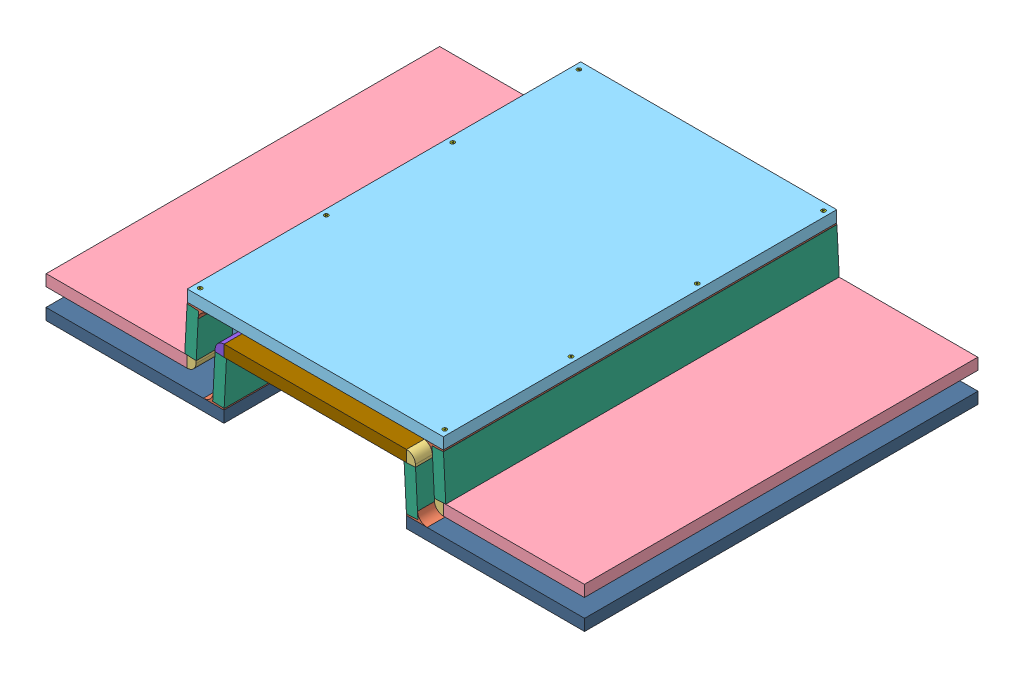
SolidWorks assembly Assemblage moule, configuration Default. Lengths in mm.
Overall size (752.9 137 550).
38 component instances, 11 part files, 25 mates.
Components (placement in the parent):
- Plancher simple-1: Plancher simple [Default] at (125.6276 24.22 73.6954) size (658.2 105 450)
- Female mold-1: Female mold [Default] at (-266.2243 -94.1216 86.2035) size (752.28 96 550)
  - A1-1: A1 [Default] at (542.1283 143.3416 262.4919) x (1 0 0) z (0 0 -1) size (28.69 12.79 550)
  - A1-2: A1 [Default] at (241.5754 143.3416 -287.5081) x (-1 0 0) z (0 0 1) size (28.69 12.79 550)
  - A2-1: A2 [Default] at (212.711 75.8416 262.4919) x (-1 0 0) z (0 0 -1) size (12.66 15.98 550)
  - A2-2: A2 [Default] at (570.9927 75.8416 -287.5081) size (12.66 15.98 550)
  - P1-1: P1 [Default] at (114.211 63.3416 -12.5081) x (1 0 0) z (0 1 0) size (197 550 16)
  - P1-2: P1 [Default] at (669.4927 63.3416 -12.5081) x (1 0 0) z (0 1 0) size (197 550 16)
  - P2-1: P2 [Default] at (391.8504 143.3416 -12.5081) x (1 0 0) z (0 1 0) size (357.94 550 16)
  - P3-1: P3 [Default] at (556.7069 109.5893 -12.5081) x (0 0 -1) z (0.99863 0.052336 0) size (550 61.94 16)
  - P3-2: P3 [Default] at (226.9968 109.5893 -12.5081) x (0 0 -1) z (-0.99863 0.052336 0) size (550 61.94 16)
  - 90031A117_Phillips Flat Head Screws for Wood-1: 90031A117_Phillips Flat Head Screws for Wood [90031A117] at (220.8804 143.4666 252.4919) x (0 -1 0) z (0.999698 0 -0.024591) size (31.75 5.71 5.71)
  - 90031A117_Phillips Flat Head Screws for Wood-2: 90031A117_Phillips Flat Head Screws for Wood [90031A117] at (220.8804 143.4666 75.9919) x (0 -1 0) z (0.999698 0 -0.024591) size (31.75 5.71 5.71)
  - 90031A117_Phillips Flat Head Screws for Wood-3: 90031A117_Phillips Flat Head Screws for Wood [90031A117] at (220.8804 143.4666 -100.5081) x (0 -1 0) z (0.981484 0 -0.191546) size (31.75 5.71 5.71)
  - 90031A117_Phillips Flat Head Screws for Wood-4: 90031A117_Phillips Flat Head Screws for Wood [90031A117] at (220.8804 143.4666 -277.0081) x (0 -1 0) z (-0.266658 0 -0.963791) size (31.75 5.71 5.71)
  - 90031A117_Phillips Flat Head Screws for Wood-5: 90031A117_Phillips Flat Head Screws for Wood [90031A117] at (562.8204 143.4666 252.4919) x (0 -1 0) z (0.981484 0 -0.191546) size (31.75 5.71 5.71)
  - 90031A117_Phillips Flat Head Screws for Wood-6: 90031A117_Phillips Flat Head Screws for Wood [90031A117] at (562.8204 143.4666 75.9919) x (0 -1 0) z (0.981484 0 -0.191546) size (31.75 5.71 5.71)
  - 90031A117_Phillips Flat Head Screws for Wood-7: 90031A117_Phillips Flat Head Screws for Wood [90031A117] at (562.8204 143.4666 -100.5081) x (0 -1 0) z (0.981484 0 -0.191546) size (31.75 5.71 5.71)
  - 90031A117_Phillips Flat Head Screws for Wood-8: 90031A117_Phillips Flat Head Screws for Wood [90031A117] at (562.8204 143.4666 -277.0081) x (0 -1 0) z (0.981484 0 -0.191546) size (31.75 5.71 5.71)
- anneau_rover-2: anneau_rover [Default] at (126.4473 -2.45 41.3303) size (255.02 26.67 255.02) (hidden)
- Male mold-1: Male mold [Default] at (-12.1046 77.452 -208.4078) size (752.9 96 550)
  - A4-1: A4 [Default] at (10.2322 -65.7319 557.1032) x (1 0 0) z (0 0 -1) size (12.66 15.98 550)
  - A1-1: A1 [Default] at (294.0966 -133.2319 557.1032) x (-1 0 0) z (0 0 -1) size (28.69 12.79 550)
  - A2-1: A2 [Default] at (265.2322 -65.7319 7.1032) x (-1 0 0) z (0 0 1) size (12.66 15.98 550)
  - A1-2: A1 [Default] at (-18.6322 -133.2319 7.1032) size (28.69 12.79 550)
  - P5-1: P5 [Default] at (137.7322 -69.2319 282.1032) x (1 0 0) z (0 1 0) size (255 550 16)
  - P3-1: P3 [Default] at (263.5399 -100.317 282.1032) x (0 0 -1) z (0.99863 0.052336 0) size (550 61.94 16)
  - P3-2: P3 [Default] at (-4.0536 -99.4805 282.1032) x (0 0 -1) z (0.99863 -0.052336 0) size (550 61.94 16)
  - P6-1: P6 [Default] at (389.7916 -133.2319 282.1032) x (-1 0 0) z (0 -1 0) size (248.78 550 16)
  - P6-2: P6 [Default] at (-114.3272 -133.2319 282.1032) x (1 0 0) z (0 -1 0) size (248.78 550 16)
  - 90031A117_Phillips Flat Head Screws for Wood-1: 90031A117_Phillips Flat Head Screws for Wood [90031A117] at (2.0628 -133.3569 17.6032) x (0 1 0) z (0.999698 0 0.024591) size (31.75 5.71 5.71)
  - 90031A117_Phillips Flat Head Screws for Wood-16: 90031A117_Phillips Flat Head Screws for Wood [90031A117] at (2.0628 -133.3569 194.1032) x (0 1 0) z (0.986419 0 -0.164247) size (31.75 5.71 5.71)
  - 90031A117_Phillips Flat Head Screws for Wood-17: 90031A117_Phillips Flat Head Screws for Wood [90031A117] at (2.0628 -133.3569 370.6032) x (0 1 0) z (0.927819 0 -0.373031) size (31.75 5.71 5.71)
  - 90031A117_Phillips Flat Head Screws for Wood-18: 90031A117_Phillips Flat Head Screws for Wood [90031A117] at (2.0628 -133.3569 547.1032) x (0 1 0) z (0.814513 0 -0.580145) size (31.75 5.71 5.71)
  - 90031A117_Phillips Flat Head Screws for Wood-19: 90031A117_Phillips Flat Head Screws for Wood [90031A117] at (273.4016 -133.3569 17.1032) x (0 1 0) z (0.652414 0 -0.757863) size (31.75 5.71 5.71)
  - 90031A117_Phillips Flat Head Screws for Wood-21: 90031A117_Phillips Flat Head Screws for Wood [90031A117] at (273.4016 -133.3569 193.6032) x (0 1 0) z (0.465534 0 -0.88503) size (31.75 5.71 5.71)
  - 90031A117_Phillips Flat Head Screws for Wood-27: 90031A117_Phillips Flat Head Screws for Wood [90031A117] at (273.4016 -133.3569 370.1032) x (0 1 0) z (0.290404 0 -0.956904) size (31.75 5.71 5.71)
  - 90031A117_Phillips Flat Head Screws for Wood-29: 90031A117_Phillips Flat Head Screws for Wood [90031A117] at (273.4016 -133.3569 546.6032) x (0 1 0) z (0.077293 0 -0.997008) size (31.75 5.71 5.71)
Mates (geometry in assembly coordinates):
- Coincident118: coincident anti-aligned: plane of Plancher simple-1 through (-203.4724 -30.78 -151.3046) normal (0 1 0); plane of Female mold-1/P1-1 through (-152.0133 -30.78 73.6954) normal (0 -1 0)
- Coincident119: coincident: point of Plancher simple-1; unknown of Female mold-1/P1-1
- Coincident121: coincident anti-aligned: plane of Plancher simple-1 through (454.7276 -30.78 -151.3046) normal (0 1 0); plane of Female mold-1/P1-2 through (403.2684 -30.78 73.6954) normal (0 -1 0)
- Coincident122: coincident: unknown of Plancher simple-1; unknown of Female mold-1/P1-2
- Coincident124: coincident anti-aligned: plane of Plancher simple-1 through (-24.6476 49.22 -151.3046) normal (0 1 0); plane of Female mold-1/P2-1 through (125.6261 49.22 73.6954) normal (0 -1 0)
- Parallel10: parallel aligned: plane of Plancher simple-1 through (-53.5133 -18.28 -151.3046) normal (0 0 -1); plane of Female mold-1/P2-1 through (-53.3439 65.22 -201.3046) normal (0 0 -1)
- Coincident125: coincident anti-aligned: plane of Plancher simple-1 through (292.2856 -18.9342 -151.3046) normal (0.99863 0.052336 0); plane of Female mold-1/P3-1 through (290.4826 15.4677 73.6954) normal (-0.99863 -0.052336 0)
- Concentric27: concentric aligned: cylinder of Plancher simple-1 through (275.9027 35.72 -151.3046) axis (0 0 1) radius 13.5; cylinder of Female mold-1/A1-1 through (275.9027 35.72 -201.3046) axis (0 0 1) radius 13.5
- Concentric28: concentric anti-aligned: cylinder of Plancher simple-1 through (-24.6476 35.72 -151.3046) axis (0 0 1) radius 13.5; cylinder of Female mold-1/A1-2 through (-24.6476 35.72 348.6954) axis (0 0 -1) radius 13.5
- Coincident126: coincident anti-aligned: plane of Plancher simple-1 through (-41.0304 -18.9342 -151.3046) normal (-0.99863 0.052336 0); plane of Female mold-1/P3-2 through (-39.2275 15.4677 73.6954) normal (0.99863 -0.052336 0)
- Concentric29: concentric aligned: cylinder of Plancher simple-1 through (-53.5133 -18.28 -151.3046) axis (0 0 1) radius 12.5; cylinder of Female mold-1/A2-1 through (-53.5133 -18.28 -201.3046) axis (0 0 1) radius 12.5
- Concentric30: concentric anti-aligned: cylinder of Plancher simple-1 through (304.7684 -18.28 -151.3046) axis (0 0 1) radius 12.5; cylinder of Female mold-1/A2-2 through (304.7684 -18.28 348.6954) axis (0 0 -1) radius 12.5
- Concentric31: concentric aligned: cylinder of Plancher simple-1 through (-1.8724 11.72 -151.3046) axis (0 0 1) radius 12.5; cylinder of Male mold-1/A4-1 through (-1.8724 11.72 -201.3046) axis (0 0 1) radius 12.5
- Coincident128: coincident aligned: line of Plancher simple-1 through (-1.8724 24.22 -137.8046) axis (0 0 1); line of Male mold-1/A4-1 through (-1.8724 24.22 -201.3046) axis (0 0 1)
- Coincident129: coincident anti-aligned: plane of Plancher simple-1 through (-1.8724 24.22 -151.3046) normal (0 -1 0); plane of Male mold-1/P5-1 through (125.6276 24.22 73.6954) normal (0 1 0)
- Coincident130: coincident: unknown of Plancher simple-1; unknown of Male mold-1/P5-1
- Coincident131: coincident anti-aligned: plane of Plancher simple-1 through (268.5118 -42.9865 -151.3046) normal (-0.99863 -0.052336 0); plane of Male mold-1/P3-1 through (267.4134 -22.0277 73.6954) normal (0.99863 0.052336 0)
- Concentric32: concentric aligned: cylinder of Plancher simple-1 through (281.9933 -42.28 -151.3046) axis (0 0 1) radius 13.5; cylinder of Male mold-1/A1-1 through (281.9933 -42.28 -201.3046) axis (0 0 1) radius 13.5
- Concentric33: concentric anti-aligned: cylinder of Plancher simple-1 through (253.1276 11.72 -151.3046) axis (0 0 1) radius 12.5; cylinder of Male mold-1/A2-1 through (253.1276 11.72 348.6954) axis (0 0 -1) radius 12.5
- Coincident132: coincident anti-aligned: plane of Plancher simple-1 through (-17.2566 -42.9865 -151.3046) normal (0.99863 -0.052336 0); plane of Male mold-1/P3-2 through (-16.1583 -22.0286 73.6954) normal (-0.99863 0.052336 0)
- Concentric34: concentric anti-aligned: cylinder of Plancher simple-1 through (-30.7381 -42.28 -151.3046) axis (0 0 1) radius 13.5; cylinder of Male mold-1/A1-2 through (-30.7381 -42.28 348.6954) axis (0 0 -1) radius 13.5
- Coincident133: coincident anti-aligned: plane of Plancher simple-1 through (454.7276 -55.78 -151.3046) normal (0 -1 0); plane of Male mold-1/P6-1 through (377.687 -55.78 73.6954) normal (0 1 0)
- Coincident135: coincident anti-aligned: plane of Plancher simple-1 through (-203.4724 -55.78 -151.3046) normal (0 -1 0); plane of Male mold-1/P6-2 through (-126.4318 -55.78 73.6954) normal (0 1 0)
- Coincident136: coincident aligned: plane of Female mold-1/P1-1 through (-250.5133 -14.78 -201.3046) normal (0 0 -1); plane of Male mold-1/P6-2 through (-250.8218 -71.78 -201.3046) normal (0 0 -1)
- Coincident137: coincident anti-aligned: plane of Plancher simple-1 through (-1.8724 24.22 -151.3046) normal (0 -1 0); plane of anneau_rover-2 through (126.4473 24.22 41.3303) normal (0 1 0)
